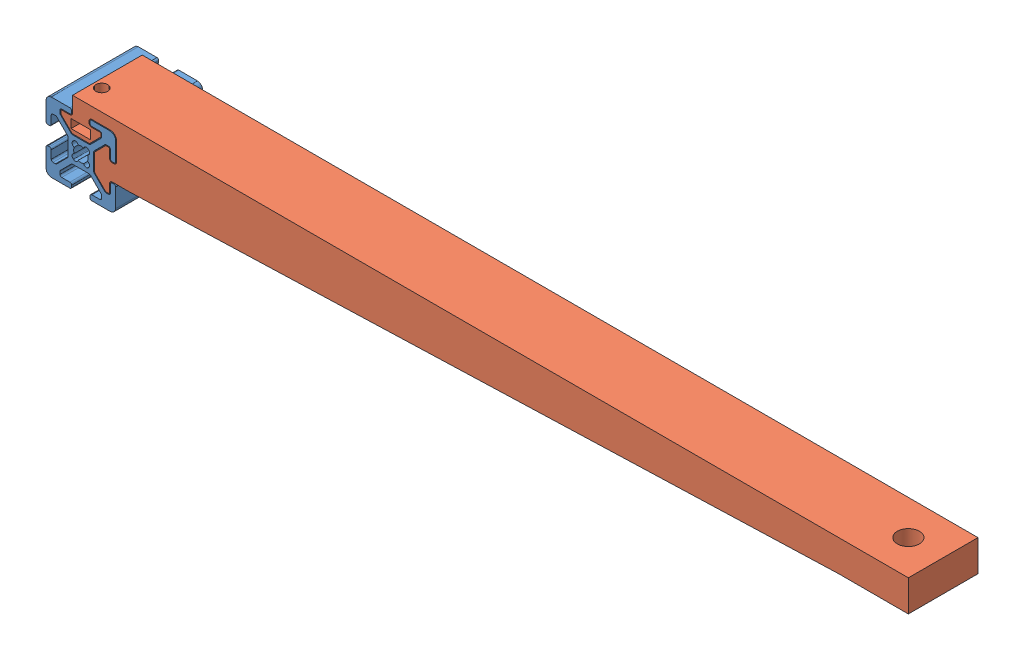
SolidWorks assembly z-axis-camera-mounts, configuration Default. Lengths in mm.
Overall size (247.62 23.49 25).
2 component instances, 2 part files, 4 mates.
Components (placement in the parent):
- 20_2020_25_CL-1: 20_2020_25_CL [Default] at origin size (20 20 25)
- mount-1: mount [Default] at origin size (243.37 19.24 20)
Mates (geometry in assembly coordinates):
- InPlace1: in place: plane of ? through (-8.5 -8.5 0) normal (0 0 1); plane of ? through (0 0 0) normal (0 0 1); moOrthogonalPlaneRef_w of ? through (-8.5 -8.5 0) normal (0 0 1); plane of ? through (0 0 0) normal (0 1 0); plane of ? through (-8.5 -8.5 0) normal (0 0 1); plane of ? through (0 0 0) normal (1 0 0); plane of ? through (-8.5 -8.5 0) normal (0 0 1); unknown of ?
- Coincident1: coincident aligned: plane of 20_2020_25_CL-1; plane of mount-1
- Coincident2: coincident aligned: moOrthogonalPlaneRef_w of 20_2020_25_CL-1 through (0 0 0) normal (0 1 0); plane of mount-1 through (0 0 0) normal (0 1 0)
- Coincident3: coincident anti-aligned: moOrthogonalPlaneRef_w of 20_2020_25_CL-1 through (0 0 0) normal (-1 0 0); plane of mount-1 through (0 0 0) normal (1 0 0)
